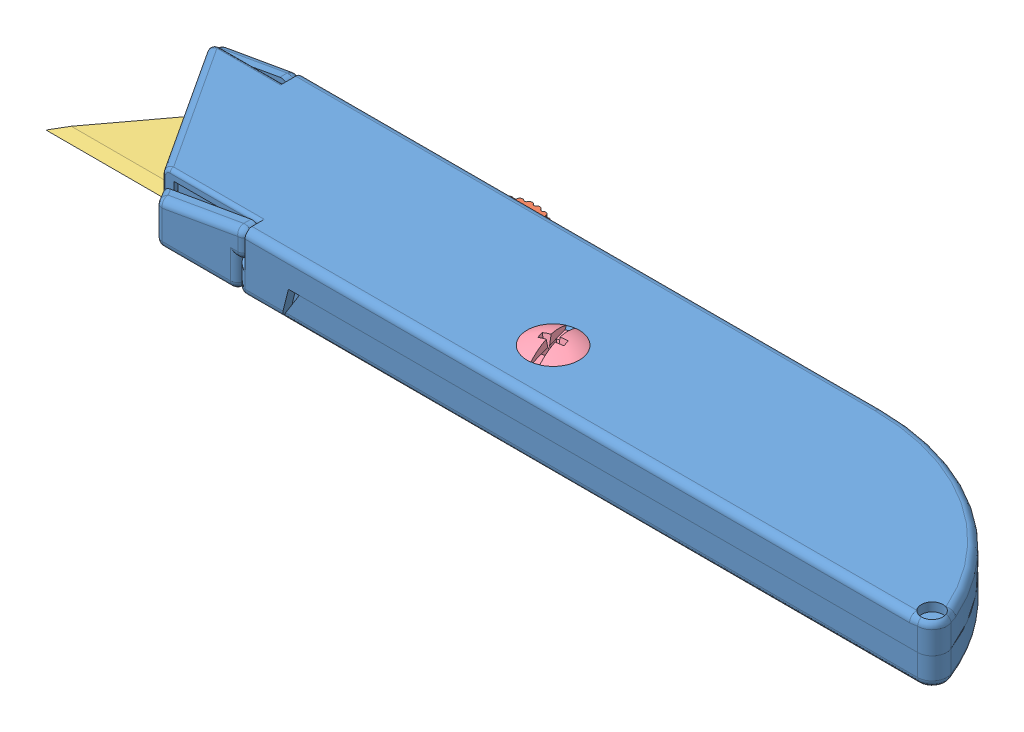
SolidWorks assembly Knife assembly, configuration Default. Lengths in mm.
Overall size (159.15 11.59 31.46).
6 component instances, 4 part files, 17 mates.
Components (placement in the parent):
- HANDLE-1: HANDLE [Default] at (0.7433 5.08 4.294) x (-1 0 0) z (0 0 1) size (153.87 10.03 29.21)
- HANDLE-2: HANDLE [handle 2nd half] at (0.7433 5.08 4.294) x (-1 0 0) z (0 0 1) size (152.25 10.16 29.21)
- BLADE HOLDER-1: BLADE HOLDER [Default] at (-113.8548 0 -8.533) x (0 0 1) z (-1 0 0) size (28.92 6.35 45.97)
- BLADE PART-1: BLADE PART [Default] at (-125.7692 -0.635 -11.734) size (60.2 0.51 19.05)
- BLADE PART-2: BLADE PART [Default] at (-40.0006 -2.286 -11.7669) size (60.2 0.51 19.05)
- STANLEY SCREW-1: STANLEY SCREW [Default] at (-72.9167 1.0995 -5.358) x (-0.269221 0 -0.963078) z (0 1 0) size (9.06 9.14 11.59)
Mates (geometry in assembly coordinates):
- Parallel1: parallel aligned: plane of HANDLE-1 through (3.2833 0 -24.916) normal (0 1 0)
- Coincident4: coincident: point of HANDLE-1
- Parallel2: parallel aligned: plane of HANDLE-1 through (0.7433 5.08 4.294) normal (0 0 1)
- Coincident5: coincident anti-aligned: plane of HANDLE-1 through (0.7433 -5.08 1.754) normal (0 0 -1); plane of BLADE HOLDER-1 through (-91.7568 1.397 1.754) normal (0 0 1)
- Parallel3: parallel anti-aligned: plane of HANDLE-1 through (-34.7031 -2.54 15.724) normal (0 1 0); plane of BLADE HOLDER-1 through (-113.8548 -1.397 -8.533) normal (0 -1 0)
- Parallel4: parallel anti-aligned: line of HANDLE-1 through (-79.1397 -2.54 -22.376) axis (1 0 0); line of BLADE HOLDER-1 through (-89.4708 -2.54 -18.82) axis (-1 0 0)
- Coincident7: coincident anti-aligned: plane of HANDLE-1 through (-34.7031 -2.54 15.724) normal (0 1 0); plane of BLADE HOLDER-1 through (-89.4708 -2.54 -12.7413) normal (0 -1 0)
- Coincident8: coincident anti-aligned: plane of HANDLE-1 through (3.2833 0 -24.916) normal (0 1 0); plane of HANDLE-2 through (-127.5267 0 109.878) normal (0 -1 0)
- Coincident10: coincident anti-aligned: line of HANDLE-1 through (0.7433 0 4.294) axis (-1 0 0); line of HANDLE-2 through (-109.7467 0 4.294) axis (1 0 0)
- Coincident11: coincident anti-aligned: plane of HANDLE-1 through (-118.6367 0 -15.5199) normal (1 0 0); plane of HANDLE-2 through (-118.6367 0 -16.3811) normal (-1 0 0)
- Coincident12: coincident anti-aligned: plane of BLADE HOLDER-1 through (-113.8548 -0.889 -8.533) normal (0 1 0); plane of BLADE PART-1 through (-125.7692 -0.889 -11.734) normal (0 -1 0)
- Coincident16: coincident anti-aligned: plane of BLADE HOLDER-1 through (-135.9528 1.397 -18.312) normal (0 0 1); plane of BLADE PART-1 through (-109.8942 -0.381 -18.312) normal (0 0 -1)
- Coincident17: coincident anti-aligned: plane of HANDLE-1 through (-34.7031 -2.54 15.724) normal (0 1 0); plane of BLADE PART-2 through (-40.0006 -2.54 -11.7669) normal (0 -1 0)
- Coincident23: coincident: point of BLADE HOLDER-1; line of BLADE PART-1 through (-97.5668 -0.889 -1.802) axis (-0.598289 0 -0.80128)
- LimitDistance1: limit distance = 15.3882 mm anti-aligned: plane of BLADE HOLDER-1 through (-94.5508 -0.889 -18.185) normal (1 0 0); plane of HANDLE-2 through (-79.1626 1.27 16.7601) normal (-1 0 0)
- Concentric2: concentric anti-aligned: circle of Handle-2; circle of Stanley screw-1
- Coincident24: coincident aligned: circle of Handle-2; circle of Stanley screw-1
